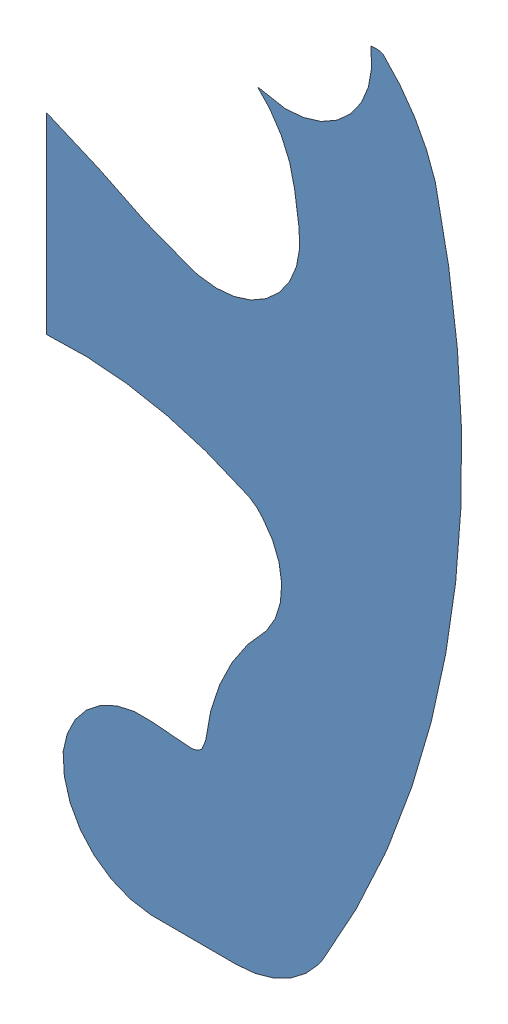
SolidWorks assembly Assem1, configuration Default. Lengths in mm.
Overall size (71.68 148.95 0).
2 component instances, 2 part files, 1 mates.
Components (placement in the parent):
- left grip back narrow-1: left grip back narrow [Default] at (38.992 186.4344 205.0808) size (267.09 171.6 32.62) (hidden)
- learning surfacing-1: learning surfacing [Default] at (94.3943 148.5752 220.0808) size (71.68 148.95 0)
Mates (geometry in assembly coordinates):
- Coincident1: coincident aligned: plane of left grip back narrow-1 through (38.992 186.4344 220.0808) normal (0 0 1); plane of learning surfacing-1 through (144.6409 244.2859 220.0808) normal (0 0 1)
